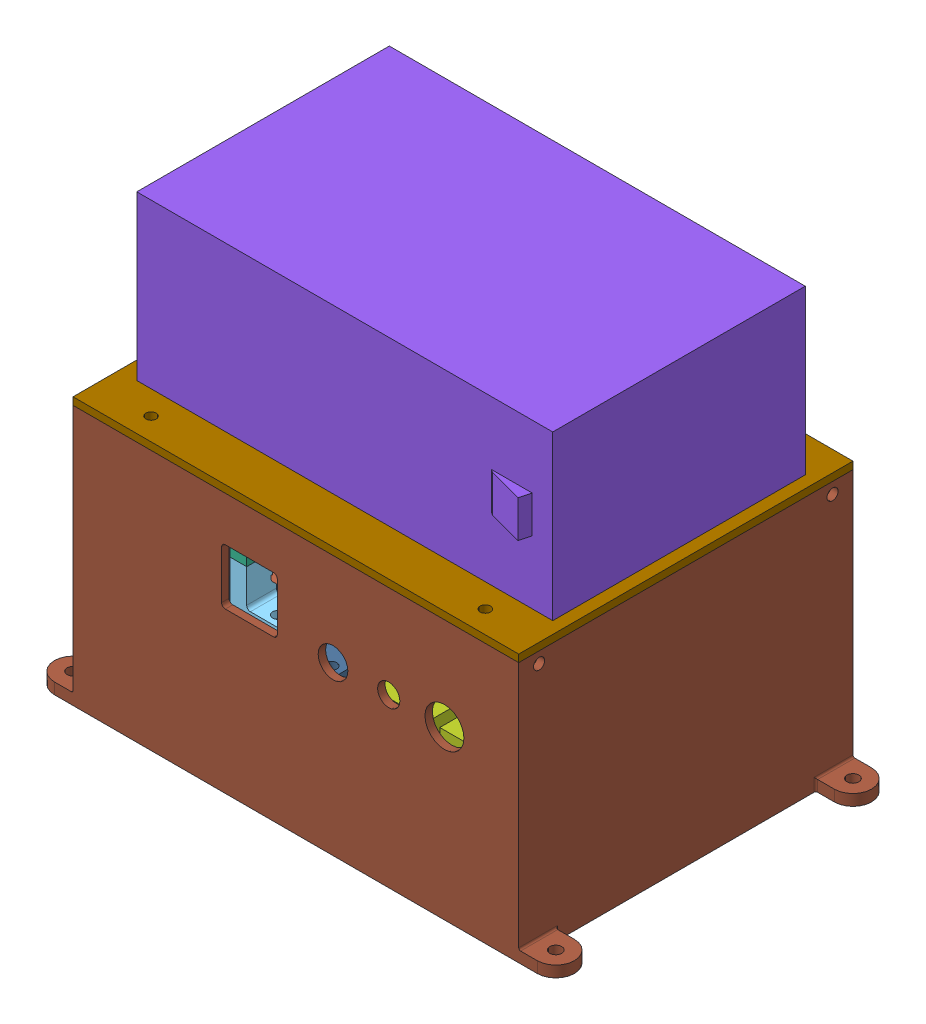
SolidWorks assembly 控制器V3.0, configuration 默认. Lengths in mm.
Overall size (140 116 90).
23 component instances, 11 part files, 53 mates.
Components (placement in the parent):
- 继电器-1: 继电器 [默认] at (-42.5 40 3) x (0 0 1) z (-1 0 0) size (50 16.5 25)
- 控制板-1: 控制板 [默认] at (-12.5 44 6) x (0 0 1) z (1 0 0) size (44.5 4.5 17)
- 铜柱2.5x14-1: 铜柱2.5x14 [默认] at (4.5 30 -33.25) x (0.992375 0 0.123257) z (0.123257 0 -0.992375) size (4.62 20 4)
- 铜柱2.5x14-4: 铜柱2.5x14 [默认] at (4.5 16 -33.25) x (0.127193 0 -0.991878) z (-0.991878 0 -0.127193) size (4.62 20 4)
- 铜柱2.5x8-1: 铜柱2.5x8 [默认] at (-52.5 32 -19.5) x (-0.890446 0 0.45509) z (-0.45509 0 -0.890446) size (5.2 14 4.5)
- 铜柱2.5x8-2: 铜柱2.5x8 [默认] at (-32.5 32 25.5) x (0.068247 0 0.997668) z (-0.997668 0 0.068247) size (5.2 14 4.5)
- 铜柱2.5x8-5: 铜柱2.5x8 [默认] at (-52.5 40 25.5) x (0.492798 0 0.870144) z (0.870144 0 -0.492798) size (5.2 14 4.5)
- 铜柱2.5x8-9: 铜柱2.5x8 [默认] at (-32.5 32 -19.5) x (-0.892937 0 0.450182) z (-0.450182 0 -0.892937) size (5.2 14 4.5)
- 底座-1: 底座 [默认] at (-12.5 32 -17.5) size (20 12 8)
- 底座-2: 底座 [默认] at (-12.5 32 29.5) x (-1 0 0) z (0 0 -1) size (20 12 8)
- 固定盖-1: 固定盖 [默认] at (-12.5 44 25.5) size (20 4.5 8)
- 固定盖-2: 固定盖 [默认] at (-12.5 44 -13.5) x (-1 0 0) z (0 0 -1) size (20 4.5 8)
- 电源降压模块-1: 电源降压模块 [默认] at origin size (115 27 76)
- 锂电池-1: 锂电池 [默认] at (-55.2132 87 -8.1236) x (0 0 -1) z (0 -1 0) size (71 112 44)
- 铜柱2.5x14-19: 铜柱2.5x14 [默认] at (4.5 16 33.25) x (0.870616 0 -0.491963) z (-0.491963 0 -0.870616) size (4.62 20 4)
- 铜柱2.5x14-20: 铜柱2.5x14 [默认] at (4.5 30 33.25) x (0.925709 0 -0.378237) z (-0.378237 0 -0.925709) size (4.62 20 4)
- 铜柱2.5x14-21: 铜柱2.5x14 [默认] at (-54.5 16 33.25) x (0.980795 0 -0.195041) z (0.195041 0 0.980795) size (4.62 20 4)
- 铜柱2.5x14-22: 铜柱2.5x14 [默认] at (-54.5 2 33.25) x (0.655251 0 0.755411) z (-0.755411 0 0.655251) size (4.62 20 4)
- 铜柱2.5x14-23: 铜柱2.5x14 [默认] at (-54.5 16 -33.25) x (-0.248568 0 0.968614) z (-0.968614 0 -0.248568) size (4.62 20 4)
- 铜柱2.5x14-24: 铜柱2.5x14 [默认] at (-54.5 2 -33.25) x (0.655251 0 0.755411) z (-0.755411 0 0.655251) size (4.62 20 4)
- 控制盒盖-1: 控制盒盖 [默认] at (0 65 -6.75) x (1 0 0) z (0 0 -1) size (120 8 90)
- 固定板V3.0-2: 固定板V3.0 [默认] at (-25 32 0) x (1 0 0) z (0 0 -1) size (65 2 71)
- 外壳-2: 外壳 [默认] at (0 -7 -6.75) x (-1 0 0) z (0 0 -1) size (140 70 90)
Mates (geometry in assembly coordinates):
- 同心46: concentric aligned: cylinder of 继电器-1 through (-52.5 40 25.5) axis (0 1 0) radius 1.5; cylinder of 铜柱2.5x8-5 through (-52.5 34 25.5) axis (0 1 0) radius 1.25
- 同心47: concentric anti-aligned: cylinder of 继电器-1 through (-52.5 40 -19.5) axis (0 1 0) radius 1.5; cylinder of 铜柱2.5x8-1 through (-52.5 38 -19.5) axis (0 -1 0) radius 1.25
- 重合32: coincident anti-aligned: plane of 控制板-1 through (-12.5 42.5 6) normal (0 -1 0); plane of 底座-1 through (-12.5 42.5 -17.5) normal (0 1 0)
- 重合33: coincident anti-aligned: plane of 控制板-1 through (-4 42.5 -15.5) normal (0 0 -1); plane of 底座-1 through (-21.5 42.5 -15.5) normal (0 0 1)
- 宽度1: width anti-aligned: plane of 底座-1 through (-22.5 44 -21.5) normal (-1 0 0); plane of 底座-1 through (-2.5 44 -21.5) normal (1 0 0); plane of 控制板-1 through (-4 42.5 -15.5) normal (1 0 0); plane of 控制板-1 through (-21 42.5 -15.5) normal (-1 0 0)
- 重合34: coincident anti-aligned: plane of 控制板-1 through (-4 42.5 27.5) normal (0 0 1); plane of 底座-2 through (-3.5 42.5 27.5) normal (0 0 -1)
- 重合35: coincident anti-aligned: plane of 控制板-1 through (-12.5 42.5 6) normal (0 -1 0); plane of 底座-2 through (-12.5 42.5 29.5) normal (0 1 0)
- 重合36: coincident aligned: plane of 底座-1 through (-22.5 44 -21.5) normal (-1 0 0); plane of 底座-2 through (-22.5 44 33.5) normal (-1 0 0)
- 同心48: concentric anti-aligned: cylinder of 底座-2 through (-20 44 30.5) axis (0 -1 0) radius 1; cylinder of 固定盖-1 through (-20 44 30.5) axis (0 1 0) radius 1.25
- 同心49: concentric anti-aligned: cylinder of 底座-2 through (-5 44 30.5) axis (0 -1 0) radius 1; cylinder of 固定盖-1 through (-5 44 30.5) axis (0 1 0) radius 1.25
- 重合38: coincident anti-aligned: plane of 底座-2 through (-12.5 44 29.5) normal (0 1 0); plane of 固定盖-1 through (-18 44 33.5) normal (0 -1 0)
- 同心50: concentric anti-aligned: cylinder of 底座-1 through (-20 44 -18.5) axis (0 -1 0) radius 1; cylinder of 固定盖-2 through (-20 44 -18.5) axis (0 1 0) radius 1.25
- 重合39: coincident anti-aligned: plane of 底座-1 through (-12.5 44 -17.5) normal (0 1 0); plane of 固定盖-2 through (-7 44 -21.5) normal (0 -1 0)
- 同心51: concentric anti-aligned: cylinder of 底座-1 through (-5 44 -18.5) axis (0 -1 0) radius 1; cylinder of 固定盖-2 through (-5 44 -18.5) axis (0 1 0) radius 1.25
- 重合48: coincident anti-aligned: plane of 继电器-1 through (-42.5 40 3) normal (0 -1 0); plane of 铜柱2.5x8-5 through (-52.5 40 25.5) normal (0 1 0)
- 同心66: concentric aligned: cylinder of 铜柱2.5x14-1 through (4.5 10 -33.25) axis (0 1 0) radius 1.25; cylinder of 铜柱2.5x14-4 through (4.5 6 -33.25) axis (0 1 0) radius 1.25
- 重合55: coincident anti-aligned: plane of 铜柱2.5x14-1 through (4.5 16 -33.25) normal (0 -1 0); plane of 铜柱2.5x14-4 through (4.5 16 -33.25) normal (0 1 0)
- 重合57: coincident anti-aligned: plane of 铜柱2.5x14-4 through (4.5 2 -33.25) normal (0 -1 0); plane of 电源降压模块-1 through (0 2 0) normal (0 1 0)
- 同心73: concentric anti-aligned: cylinder of 继电器-1 through (-32.5 40 -19.5) axis (0 1 0) radius 1.5; cylinder of 铜柱2.5x8-9 through (-32.5 46 -19.5) axis (0 -1 0) radius 1.25
- 重合62: coincident anti-aligned: plane of 继电器-1 through (-42.5 40 3) normal (0 -1 0); plane of 铜柱2.5x8-2 through (-32.5 40 25.5) normal (0 1 0)
- 重合65: coincident anti-aligned: plane of 铜柱2.5x14-19 through (4.5 16 33.25) normal (0 1 0); plane of 铜柱2.5x14-20 through (4.5 16 33.25) normal (0 -1 0)
- 同心78: concentric aligned: cylinder of 铜柱2.5x14-19 through (4.5 6 33.25) axis (0 1 0) radius 1.25; cylinder of 铜柱2.5x14-20 through (4.5 10 33.25) axis (0 1 0) radius 1.25
- 重合66: coincident anti-aligned: plane of 铜柱2.5x14-21 through (-54.5 16 33.25) normal (0 -1 0); plane of 铜柱2.5x14-22 through (-54.5 16 33.25) normal (0 1 0)
- 同心79: concentric aligned: cylinder of 铜柱2.5x14-21 through (-54.5 26 33.25) axis (0 -1 0) radius 1.25; cylinder of 铜柱2.5x14-22 through (-54.5 22 33.25) axis (0 -1 0) radius 1.25
- 重合67: coincident anti-aligned: plane of 电源降压模块-1 through (0 2 0) normal (0 1 0); plane of 铜柱2.5x14-19 through (4.5 2 33.25) normal (0 -1 0)
- 重合69: coincident anti-aligned: plane of 铜柱2.5x14-23 through (-54.5 16 -33.25) normal (0 -1 0); plane of 铜柱2.5x14-24 through (-54.5 16 -33.25) normal (0 1 0)
- 同心82: concentric aligned: cylinder of 铜柱2.5x14-23 through (-54.5 26 -33.25) axis (0 -1 0) radius 1.25; cylinder of 铜柱2.5x14-24 through (-54.5 22 -33.25) axis (0 -1 0) radius 1.25
- 重合71: coincident anti-aligned: plane of 继电器-1 through (-42.5 40 3) normal (0 -1 0); plane of 铜柱2.5x8-1 through (-52.5 40 -19.5) normal (0 1 0)
- 重合79: coincident anti-aligned: plane of 锂电池-1 through (56.7868 65 25.8764) normal (0 -1 0); plane of 控制盒盖-1 through (0 65 -6.75) normal (0 1 0)
- 同心93: concentric anti-aligned: cylinder of 电源降压模块-1 through (-54.5 0 -33.25) axis (0 1 0) radius 1.25; cylinder of 铜柱2.5x14-24 through (-54.5 12 -33.25) axis (0 -1 0) radius 1.25
- 同心94: concentric anti-aligned: cylinder of 电源降压模块-1 through (-54.5 0 33.25) axis (0 1 0) radius 1.25; cylinder of 铜柱2.5x14-22 through (-54.5 12 33.25) axis (0 -1 0) radius 1.25
- 同心95: concentric anti-aligned: cylinder of 继电器-1 through (-32.5 40 25.5) axis (0 1 0) radius 1.5; cylinder of 铜柱2.5x8-2 through (-32.5 46 25.5) axis (0 -1 0) radius 1.25
- 重合106: coincident anti-aligned: plane of 继电器-1 through (-42.5 40 3) normal (0 -1 0); plane of 铜柱2.5x8-9 through (-32.5 40 -19.5) normal (0 1 0)
- 同心97: concentric anti-aligned: cylinder of 铜柱2.5x8-5 through (-52.5 26 25.5) axis (0 1 0) radius 1.25; cylinder of 固定板V3.0-2 through (-52.5 32 25.5) axis (0 -1 0) radius 1.25
- 重合107: coincident aligned: circle of 铜柱2.5x8-2; cylinder of 固定板V3.0-2 through (-32.5 32 25.5) axis (0 -1 0) radius 1.25
- 重合108: coincident anti-aligned: plane of 铜柱2.5x8-5 through (-52.5 32 25.5) normal (0 -1 0); plane of 固定板V3.0-2 through (-25 32 0) normal (0 1 0)
- 同心98: concentric anti-aligned: cylinder of 底座-2 through (-12.5 32 30.5) axis (0 1 0) radius 1.5; cylinder of 固定板V3.0-2 through (-12.5 32 30.5) axis (0 -1 0) radius 1.4
- 同心99: concentric anti-aligned: cylinder of 底座-1 through (-12.5 32 -18.5) axis (0 1 0) radius 1.5; cylinder of 固定板V3.0-2 through (-12.5 32 -18.5) axis (0 -1 0) radius 1.4
- 重合109: coincident anti-aligned: plane of 底座-2 through (-12.5 32 29.5) normal (0 -1 0); plane of 固定板V3.0-2 through (-25 32 0) normal (0 1 0)
- 同心100: concentric aligned: cylinder of 铜柱2.5x14-21 through (-54.5 36 33.25) axis (0 -1 0) radius 1.25; cylinder of 固定板V3.0-2 through (-54.5 32 33.25) axis (0 -1 0) radius 1.5
- 同心101: concentric aligned: cylinder of 铜柱2.5x14-23 through (-54.5 36 -33.25) axis (0 -1 0) radius 1.25; cylinder of 固定板V3.0-2 through (-54.5 32 -33.25) axis (0 -1 0) radius 1.5
- 重合110: coincident anti-aligned: plane of 铜柱2.5x14-23 through (-54.5 30 -33.25) normal (0 1 0); plane of 固定板V3.0-2 through (-25 30 0) normal (0 -1 0)
- 重合111: coincident anti-aligned: plane of 铜柱2.5x14-1 through (4.5 30 -33.25) normal (0 1 0); plane of 固定板V3.0-2 through (-25 30 0) normal (0 -1 0)
- 重合115: coordinate: point of 电源降压模块-1
- 同心102: concentric anti-aligned: cylinder of 铜柱2.5x14-20 through (4.5 20 33.25) axis (0 1 0) radius 1.25; cylinder of 固定板V3.0-2 through (4.5 32 33.25) axis (0 -1 0) radius 1.5
- 同心103: concentric anti-aligned: cylinder of 铜柱2.5x14-1 through (4.5 20 -33.25) axis (0 1 0) radius 1.25; cylinder of 固定板V3.0-2 through (4.5 32 -33.25) axis (0 -1 0) radius 1.5
- 重合116: coincident anti-aligned: plane of 铜柱2.5x14-21 through (-54.5 30 33.25) normal (0 1 0); circle of 固定板V3.0-2
- 同心106: concentric aligned: cylinder of 控制盒盖-1 through (47.5 60 -46.25) axis (1 0 0) radius 1.4; cylinder of 外壳-2 through (-60 60 -46.25) axis (1 0 0) radius 1.5
- 同心107: concentric aligned: cylinder of 控制盒盖-1 through (47.5 60 32.75) axis (1 0 0) radius 1.4; cylinder of 外壳-2 through (-60 60 32.75) axis (1 0 0) radius 1.5
- 重合118: coincident aligned: plane of 控制盒盖-1 through (-60 63 38.25) normal (-1 0 0); plane of 外壳-2 through (-60 63 38.25) normal (-1 0 0)
- 同心110: concentric aligned: cylinder of 电源降压模块-1 through (-54.5 0 33.25) axis (0 1 0) radius 1.25; cylinder of 外壳-2 through (-54.5 -7 33.25) axis (0 1 0) radius 1.25
- 同心111: concentric aligned: cylinder of 电源降压模块-1 through (54.5 0 33.25) axis (0 1 0) radius 1.25; cylinder of 外壳-2 through (54.5 -7 33.25) axis (0 1 0) radius 1.25
- 重合119: coincident anti-aligned: plane of 电源降压模块-1 through (0 0 0) normal (0 -1 0); plane of 外壳-2 through (0 0 -6.75) normal (0 1 0)
